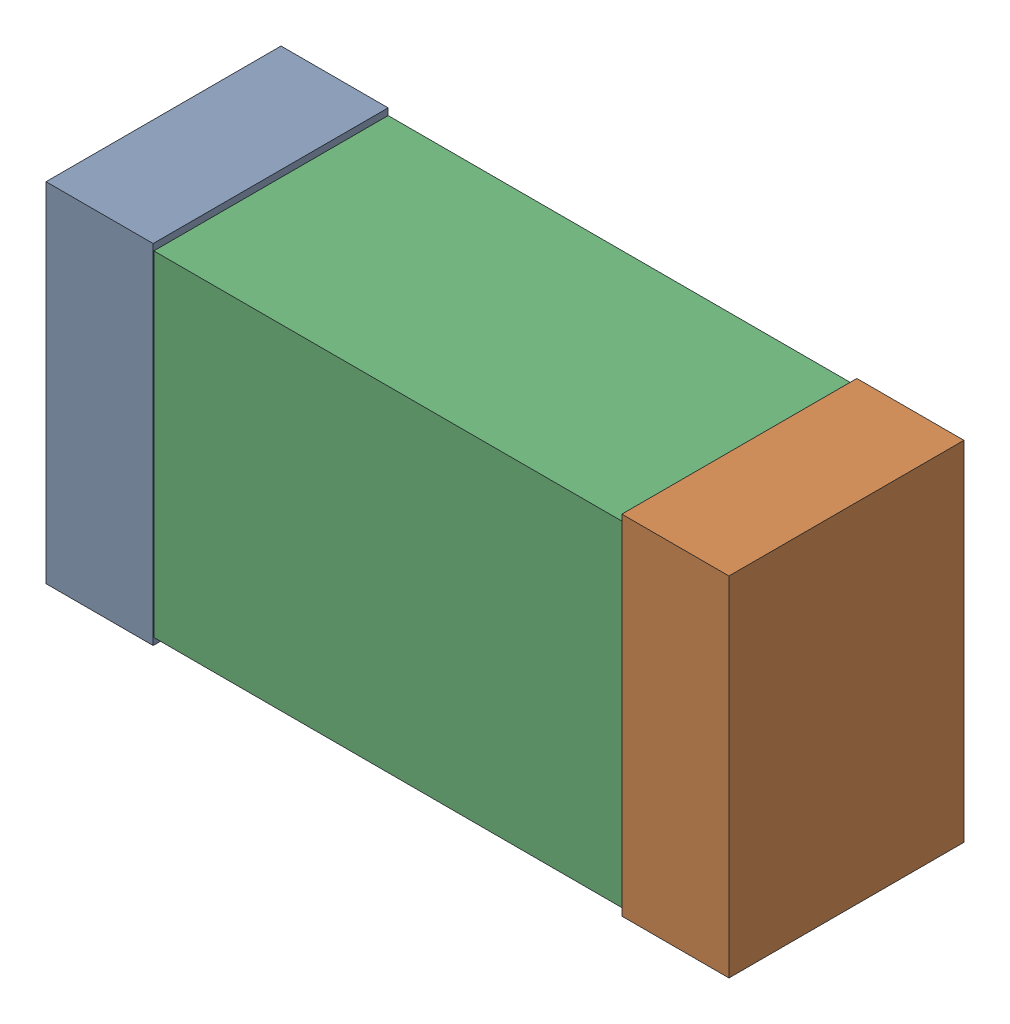
SolidWorks assembly C43, configuration Default. Lengths in mm.
Overall size (1.02 0.52 0.35).
6 component instances, 2 part files, 0 mates.
Components (placement in the parent):
- 870940480-1: 870940480 [Default] at (76.455 43 0) size (0.16 0.52 0.35)
  - Extruded-1: Extruded [Default] at origin size (0.16 0.52 0.35)
- 870940480-2: 870940480 [Default] at (77.315 43 0) size (0.16 0.52 0.35)
  - Extruded-1: Extruded [Default] at origin size (0.16 0.52 0.35)
- 870940640-1: 870940640 [Default] at (76.885 43 0) size (1 0.5 0.35)
  - Extruded_2-1: Extruded_2 [Default] at origin size (1 0.5 0.35)
